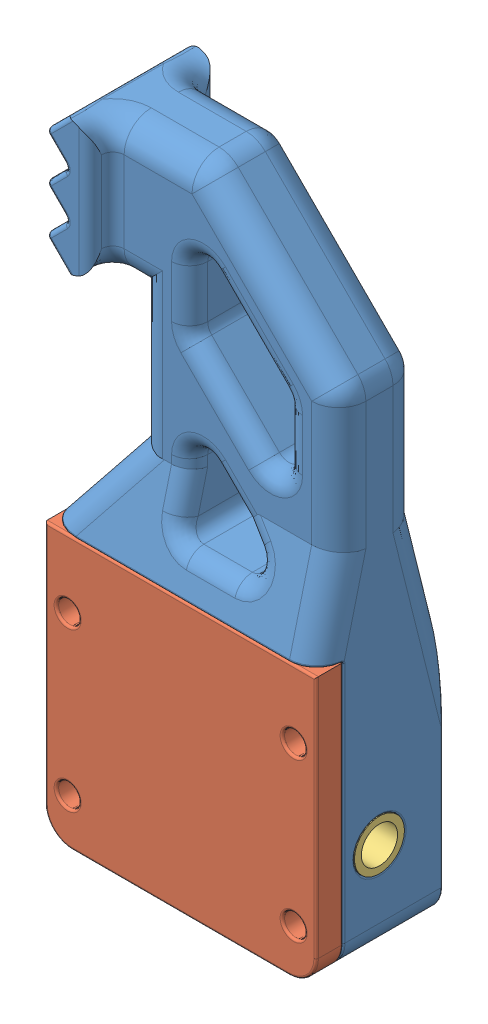
SolidWorks assembly UOM20-4A006, configuration Default. Lengths in mm.
Overall size (60.07 140.34 28.19).
7 component instances, 6 part files, 15 mates.
Components (placement in the parent):
- UOM20-4P011-1: UOM20-4P011 [Default] at (-5.5057 4.0308 33.7005) size (60.07 140.34 28.19)
- UOM20-4P036-1: UOM20-4P036 [Default] at (54.4943 4.0308 61.7005) x (-1 0 0) z (0 0 -1) size (60 60 6)
- 6659K676_OIL-EMBEDDED FLANGED SLEEVE BEARING-1: 6659K676_OIL-EMBEDDED FLANGED SLEEVE BEARING [6659K676] at (4.4943 25.0308 47.7005) x (0 -0.441612 0.897206) z (0 -0.897206 -0.441612) size (14 10 14)
- 6659K676_OIL-EMBEDDED FLANGED SLEEVE BEARING-2: 6659K676_OIL-EMBEDDED FLANGED SLEEVE BEARING [6659K676] at (44.4943 25.0308 47.7005) x (0 -0.999819 0.019038) z (0 0.019038 0.999819) size (14 10 14)
- 9434K135_MUSIC-WIRE STEEL COMPRESSION SPRINGS-1: 9434K135_MUSIC-WIRE STEEL COMPRESSION SPRINGS [9434K135] at (36.2443 25.1246 46.92) x (0 1 0) z (0 0 1) size (15.72 32.66 15.84)
- leadnut-1: leadnut [Default] at (35.2443 25.0308 47.7005) x (1 0 0) z (0 0 -1) size (10 24 10.5)
- UOM20-4P038-1: UOM20-4P038 [Default] at (43.2443 38.0308 55.7005) x (0 0 -1) z (-1 0 0) size (16 26 7)
Mates (geometry in assembly coordinates):
- Coincident3: coincident anti-aligned: plane of UOM20-4P035-1 through (-5.5057 4.0308 55.7005) normal (0 0 1); plane of UOM20-4P036-1 through (54.4943 4.0308 55.7005) normal (0 0 -1)
- Concentric1: concentric anti-aligned: cylinder of UOM20-4P035-1 through (49.4943 14.0308 55.7005) axis (0 0 1) radius 2.5; cylinder of UOM20-4P036-1 through (49.4943 14.0308 55.7005) axis (0 0 -1) radius 2.5
- Concentric2: concentric anti-aligned: cylinder of UOM20-4P035-1 through (49.4943 49.0308 55.7005) axis (0 0 1) radius 2.5; cylinder of UOM20-4P036-1 through (49.4943 49.0308 55.7005) axis (0 0 -1) radius 2.5
- Concentric4: concentric aligned: cylinder of lin block main-1 through (-5.5057 25.0308 47.7005) axis (1 0 0) radius 5.515; cylinder of 6659K676_OIL-EMBEDDED FLANGED SLEEVE BEARING-1 through (-5.5057 25.0308 47.7005) axis (1 0 0) radius 5.515
- Coincident4: coincident anti-aligned: plane of UOM20-4P035-1 through (2.9943 25.0308 47.7005) normal (1 0 0); plane of 6659K676_OIL-EMBEDDED FLANGED SLEEVE BEARING-1 through (2.9943 25.0308 47.7005) normal (-1 0 0)
- Concentric5: concentric anti-aligned: cylinder of 6659K676_OIL-EMBEDDED FLANGED SLEEVE BEARING-1 through (-5.5057 25.0308 47.7005) axis (1 0 0) radius 4.005; cylinder of 6659K676_OIL-EMBEDDED FLANGED SLEEVE BEARING-2 through (54.4943 25.0308 47.7005) axis (-1 0 0) radius 5.515
- Coincident5: coincident anti-aligned: plane of UOM20-4P035-1 through (45.9943 25.0308 47.7005) normal (-1 0 0); plane of 6659K676_OIL-EMBEDDED FLANGED SLEEVE BEARING-2 through (45.9943 25.0308 47.7005) normal (1 0 0)
- Coincident8: coincident anti-aligned: plane of leadnut-1 through (39.7443 20.0308 47.7005) normal (-1 0 0); plane of UOM20-4P038-1 through (39.7443 38.0308 55.7005) normal (1 0 0)
- Concentric6: concentric anti-aligned: cylinder of leadnut-1 through (8.0181 25.0308 47.7005) axis (-1 0 0) radius 5; cylinder of UOM20-4P038-1 through (36.2443 25.0308 47.7005) axis (1 0 0) radius 5
- Concentric9: concentric aligned: cylinder of 6659K676_OIL-EMBEDDED FLANGED SLEEVE BEARING-1 through (-5.5057 25.0308 47.7005) axis (1 0 0) radius 4.005; circle of leadnut-1
- Coincident10: coincident anti-aligned: plane of leadnut-1 through (35.2443 10.0884 52.9505) normal (0 0 1); plane of UOM20-4P038-1 through (39.7443 14.2402 52.9505) normal (0 0 -1)
- Coincident11: coincident aligned: plane of UOM20-4P035-1 through (-5.5057 4.0308 55.7005) normal (0 0 1); plane of UOM20-4P038-1 through (39.7443 38.0308 55.7005) normal (0 0 1)
- Coincident12: coincident anti-aligned: plane of 6659K676_OIL-EMBEDDED FLANGED SLEEVE BEARING-1 through (4.4943 25.0308 47.7005) normal (1 0 0); plane of 9434K135_MUSIC-WIRE STEEL COMPRESSION SPRINGS-1 through (4.4943 17.5046 39.3) normal (-1 0 0)
- Coincident13: coincident anti-aligned: plane of 9434K135_MUSIC-WIRE STEEL COMPRESSION SPRINGS-1 through (36.2443 17.5046 39.3) normal (1 0 0); plane of UOM20-4P038-1 through (36.2443 38.0308 55.7005) normal (-1 0 0)
- Lock1: lock: unknown of 9434K135_MUSIC-WIRE STEEL COMPRESSION SPRINGS-1; unknown of UOM20-4P038-1
